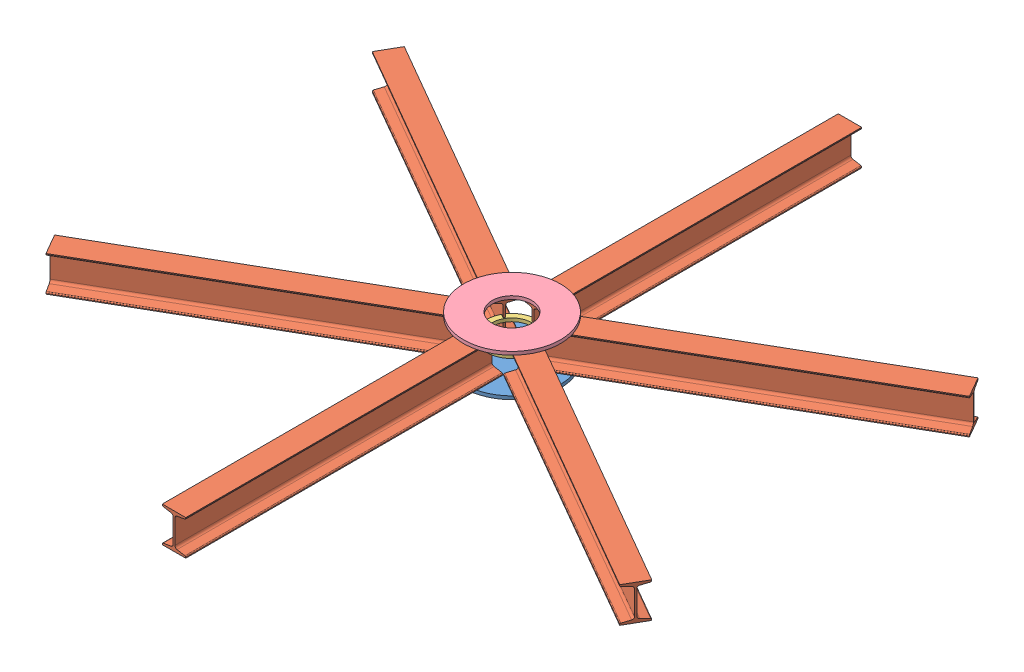
SolidWorks assembly ground_anchor, configuration Default. Lengths in mm.
Overall size (1722.09 120.65 1949.45).
10 component instances, 5 part files, 6 mates.
Components (placement in the parent):
- Copy of ground_anchor_ref^ground_anchor-1: Copy of ground_anchor_ref^ground_anchor [Default] at origin size (279.4 0 279.4) (virtual)
- low_plate^ground_anchor-1: low_plate^ground_anchor [Default] at origin size (279.4 9.53 279.4) (virtual)
- S Section_AI-1: S Section_AI [S4x7.7x36] at (-33.8201 9.525 -517.525) size (67.64 101.6 914.4)
- S Section_AI-3: S Section_AI [S4x7.7x36] at (-465.0998 9.525 -229.4734) x (0.5 0 -0.866025) z (0.866025 0 0.5) size (67.64 101.6 914.4)
- S Section_AI-4: S Section_AI [S4x7.7x36] at (-431.2797 9.525 288.0516) x (-0.5 0 -0.866025) z (0.866025 0 -0.5) size (67.64 101.6 914.4)
- S Section_AI-5: S Section_AI [S4x7.7x36] at (33.8201 9.525 517.525) x (-1 0 0) z (0 0 -1) size (67.64 101.6 914.4)
- S Section_AI-6: S Section_AI [S4x7.7x36] at (465.0998 9.525 229.4734) x (-0.5 0 0.866025) z (-0.866025 0 -0.5) size (67.64 101.6 914.4)
- S Section_AI-7: S Section_AI [S4x7.7x36] at (431.2797 9.525 -288.0516) x (0.5 0 0.866025) z (-0.866025 0 0.5) size (67.64 101.6 914.4)
- mid_plate^ground_anchor-2: mid_plate^ground_anchor [Default] at origin size (146.05 9.53 146.05) (virtual)
- top_plate^ground_anchor-1: top_plate^ground_anchor [Default] at (0 111.125 0) x (-1 0 0) z (0 1 0) size (279.4 279.4 9.53) (virtual)
Mates (geometry in assembly coordinates):
- Coincident14: coincident: point of low_plate^ground_anchor-1; moEndPointRef_w of S Section_AI-1
- Coincident16: coincident anti-aligned: plane of low_plate^ground_anchor-1 through (0 9.525 0) normal (0 1 0); plane of S Section_AI-1 through (33.8201 9.525 -60.325) normal (0 -1 0)
- Perpendicular3: perpendicular: line of low_plate^ground_anchor-1 through (0 9.525 -57.15) axis (0 0 -1); line of S Section_AI-1 through (33.8201 9.525 -60.325) axis (-1 0 0)
- Coincident24: coincident anti-aligned: plane of S Section_AI-1 through (-33.8201 111.125 -60.325) normal (0 1 0); plane of top_plate^ground_anchor-1 through (0 111.125 0) normal (0 -1 0)
- mid_cut_plane: unknown: plane of ? through (0 9.525 0) normal (0 1 0); unknown of ?; unknown of ?; sketch_entity of ?; unknown of ?
- top_plate: unknown: plane of S Section_AI-1 through (-33.8201 111.125 -60.325) normal (0 1 0)
